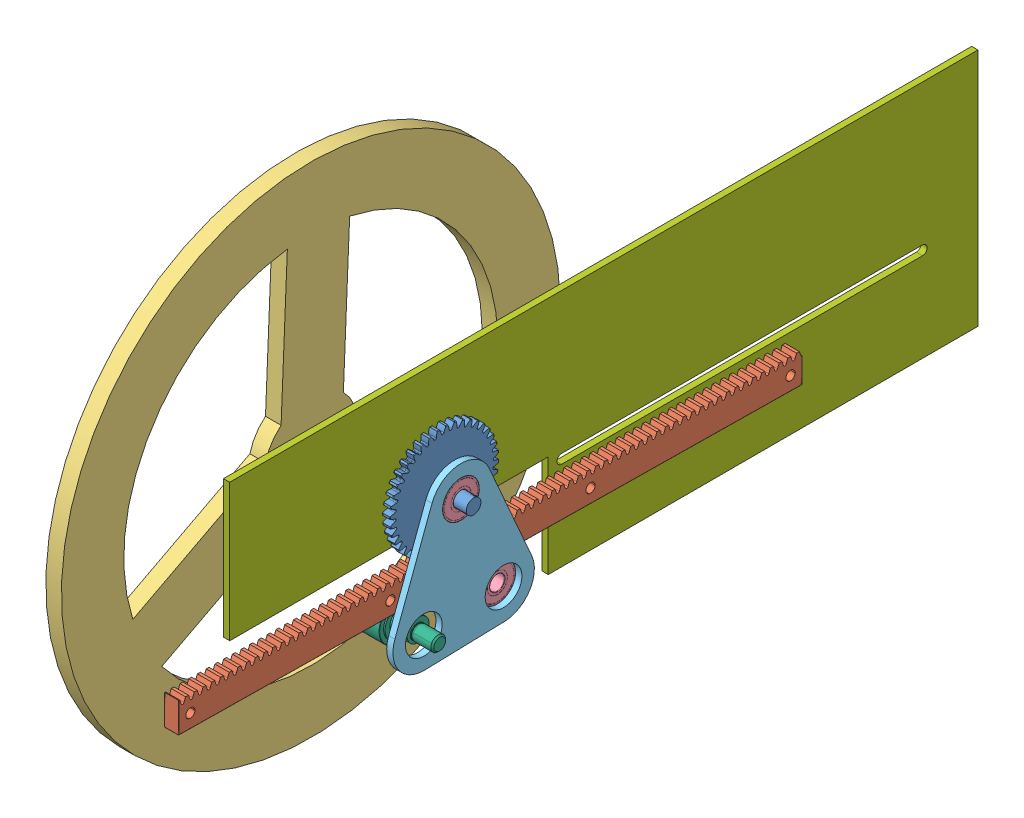
SolidWorks assembly ProgressiveSteering, configuration Default. Lengths in mm.
Overall size (73.46 211.53 342.89).
8 component instances, 7 part files, 24 mates.
Components (placement in the parent):
- SI_sdpsi_s1268z-024s040-2: SI_sdpsi_s1268z-024s040 [Default] at (1.5875 12.6889 -0.5317) x (1 0 0) z (0 0.041865 0.999123) size (65.8 44.45 44.45)
- SI_sdpsi_s1811y-rc-1a-1: SI_sdpsi_s1811y-rc-1a [Default] at (1.5875 -14.0223 -17.8811) x (0 0.013013 0.999915) z (-1 0 0) size (254.01 12.19 5.85)
- steering wheel-1: steering wheel [Default] at (-57.15 0 0) x (0 -0.041865 -0.999123) z (1 0 0) size (203.2 203.2 6.35)
- 4668K121_Permanently Lubricated Stainless Steel Ball Bearing-1: 4668K121_Permanently Lubricated Stainless Steel Ball Bearing [4668K121] at (7.34 12.6889 -0.5317) x (0 0 1) z (-1 0 0) size (15 15 5)
- Part1^ProgressiveSteering-1: Part1^ProgressiveSteering [Default] at (7.3076 -12.5093 -47.3579) x (0 0.027647 -0.999618) z (1 0 0) size (57.65 65.11 2.53) (virtual)
- 4668K121_Permanently Lubricated Stainless Steel Ball Bearing-2: 4668K121_Permanently Lubricated Stainless Steel Ball Bearing [4668K121] at (4.8076 -26.7989 -17.8747) x (0 0 -1) z (1 0 0) size (15 15 5)
- SKF_KRE_16_PP-1: SKF_KRE_16_PP [Default] at (-11.8924 -27.6971 14.6022) x (1 0 0) z (0 0.434448 0.900697) size (28.2 16 16)
- slot-2: slot [Default] at (-27.6978 -34.5663 -58.63) x (0 -0.000349 1) z (-1 0 0) size (304.8 97.5 2.54)
Mates (geometry in assembly coordinates):
- Coincident6: coincident anti-aligned: circle of SI_sdpsi_s1268z-024s040-2
- Coincident8: coincident: point of SI_sdpsi_s1268z-024s040-2; point of assembly
- Coincident13: coincident anti-aligned: plane of SI_sdpsi_s1268z-024s040-2 through (1.5875 12.6889 -0.5317) normal (1 0 0); plane of SI_sdpsi_s1811y-rc-1a-1 through (1.5875 -14.0223 -17.8811) normal (-1 0 0)
- Distance1: distance = 21.082 mm: line of assembly; point of SI_sdpsi_s1268z-024s040-2; line of SI_sdpsi_s1811y-rc-1a-1 through (1.5875 -6.8786 111.3876) axis (0 -0.013013 -0.999915)
- RackPinionMate2: rack pinion = 45.212 mm: line of SI_sdpsi_s1811y-rc-1a-1 through (-1.3335 -21.6417 -144.6657) axis (0 0.013013 0.999915); cylinder of SI_sdpsi_s1268z-024s040-2 through (0 12.6889 -0.5317) axis (1 0 0) radius 22.225
- Tangent1: tangent anti-aligned: cylinder of SI_sdpsi_s1811y-rc-1a-1 through (-1.3335 -16.1718 -140.1137) axis (-1 0 0) radius 1.8669; plane of slot-2 through (-12.7 -18.014 -211.1034) normal (0 1 0.000349)
- Concentric6: concentric anti-aligned: cylinder of SI_sdpsi_s1268z-024s040-2 through (-50.8 0 0) axis (1 0 0) radius 6.35; cylinder of steering wheel-1 through (-50.8 0 0) axis (-1 0 0) radius 19.05
- Coincident21: coincident anti-aligned: plane of SI_sdpsi_s1268z-024s040-2 through (-50.8 0 0) normal (-1 0 0); plane of steering wheel-1 through (-50.8 0 0) normal (1 0 0)
- Coincident22: coincident: line of SI_sdpsi_s1268z-024s040-2 through (0 34.63 -1.451) axis (0 -0.999123 0.041865); plane of steering wheel-1 through (-57.15 0 0) normal (0 -0.041865 -0.999123)
- Distance6: distance = 3.175 mm aligned: plane of slot-1 through (7.0485 -3.175 -260.805) normal (0 1 0)
- Concentric7: concentric anti-aligned: cylinder of SI_sdpsi_s1268z-024s040-2 through (4.84 12.6889 -0.5317) axis (1 0 0) radius 3; cylinder of 4668K121_Permanently Lubricated Stainless Steel Ball Bearing-1 through (4.84 12.6889 -0.5317) axis (-1 0 0) radius 3
- Coincident24: coincident anti-aligned: plane of SI_sdpsi_s1268z-024s040-2 through (4.84 12.6889 -0.5317) normal (1 0 0); plane of 4668K121_Permanently Lubricated Stainless Steel Ball Bearing-1 through (4.84 8.5639 -0.5317) normal (-1 0 0)
- Concentric8: concentric anti-aligned: cylinder of Part1^ProgressiveSteering-1 through (96.8058 -27.6971 14.6022) axis (-1 0 0) radius 7.5; cylinder of 4668K121_Permanently Lubricated Stainless Steel Ball Bearing-3 through (4.5085 -27.4311 18.3355) axis (1 0 0) radius 7.5
- Coincident29: coincident anti-aligned: plane of Part1^ProgressiveSteering-1 through (7.3076 12.6889 -0.5317) normal (-1 0 0); plane of 4668K121_Permanently Lubricated Stainless Steel Ball Bearing-3 through (4.5085 -30.9404 20.5036) normal (1 0 0)
- Concentric9: concentric anti-aligned: cylinder of Part1^ProgressiveSteering-1 through (96.8058 -26.7989 -17.8747) axis (-1 0 0) radius 7.5; cylinder of 4668K121_Permanently Lubricated Stainless Steel Ball Bearing-2 through (7.3076 -26.7989 -17.8747) axis (1 0 0) radius 7.5
- Coincident30: coincident anti-aligned: plane of Part1^ProgressiveSteering-1 through (7.3076 12.6889 -0.5317) normal (-1 0 0); plane of 4668K121_Permanently Lubricated Stainless Steel Ball Bearing-2 through (7.3076 -30.9239 -17.8747) normal (1 0 0)
- Concentric10: concentric aligned: circle of 4668K121_Permanently Lubricated Stainless Steel Ball Bearing-1; circle of Part1^ProgressiveSteering-1
- Tangent2: tangent anti-aligned: plane of SI_sdpsi_s1811y-rc-1a-1 through (4.5085 -21.7704 -144.791) normal (0 -0.999915 0.013013); cylinder of 4668K121_Permanently Lubricated Stainless Steel Ball Bearing-3 through (4.5085 -27.4311 18.3355) axis (1 0 0) radius 7.5
- Concentric11: concentric anti-aligned: cylinder of Part1^ProgressiveSteering-1 through (96.8058 -27.6971 14.6022) axis (-1 0 0) radius 7.5; cylinder of SKF_KRE_16_PP-1 through (16.3076 -27.6971 14.6022) axis (1 0 0) radius 3
- Coincident32: coincident anti-aligned: plane of Part1^ProgressiveSteering-1 through (7.3076 12.6889 -0.5317) normal (-1 0 0); plane of SKF_KRE_16_PP-1 through (7.3076 -23.1936 12.43) normal (1 0 0)
- Tangent3: tangent anti-aligned: plane of SI_sdpsi_s1811y-rc-1a-1 through (4.5085 -21.7704 -144.791) normal (0 -0.999915 0.013013); torus of SKF_KRE_16_PP-1
- Distance7: distance = 25.4 mm: plane of slot-1 through (7.0485 -34.2791 -85.7379) normal (1 0 0); plane of SI_sdpsi_s1811y-rc-1a-1 through (-1.3335 -14.2012 -44.3268) normal (-1 0 0)
- Distance8: distance = 12.7 mm: plane of assembly through (0 0 0) normal (1 0 0); plane of assembly; plane of slot-1 through (7.0485 -34.2791 -85.7379) normal (1 0 0)
- Distance9: distance = 15.24 mm anti-aligned: plane of slot-2 through (-15.24 -34.5663 -58.63) normal (-1 0 0)
